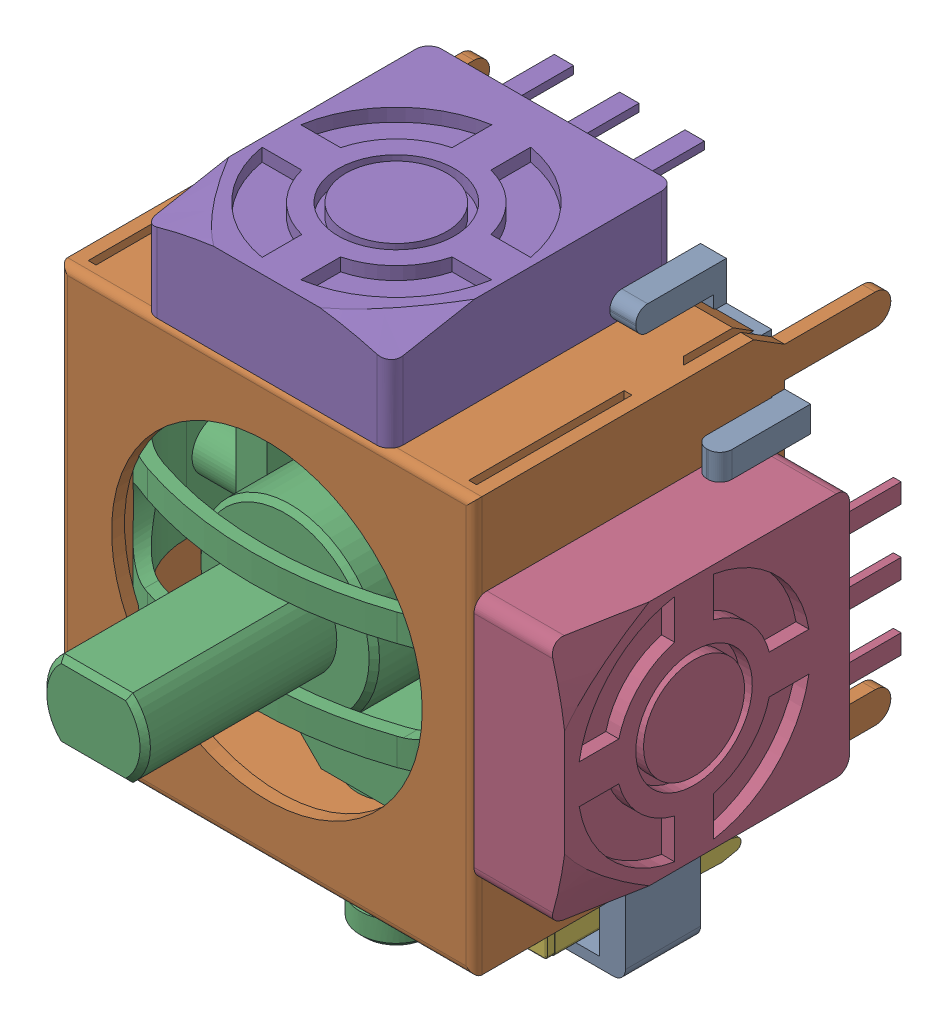
SolidWorks assembly 3D-Analog-Thumb-Joystick, configuration Default. Lengths in mm.
Overall size (20.5 25.8 22.8).
6 component instances, 6 part files, 0 mates.
Components (placement in the parent):
- Baseplate-1: Baseplate [Default] at (0 0 -7) size (18 23.3 3.5)
- Case-1: Case [Default] at origin size (16 16 16.1)
- Rotator-Unit-1: Rotator-Unit [Default] at origin size (16.2 21.5 16.2)
- Potentiometer_01-1: Potentiometer_01 [Default] at (8 0 -6) x (0 1 0) z (0 0 1) size (9.5 3.5 14)
- Potentiometer_02-1: Potentiometer_02 [Default] at (0 8 -6) x (-1 0 0) z (0 0 1) size (9.5 3.5 14)
- Tactile-Switch-1: Tactile-Switch [Default] at (0 -10.8 -6.5) x (1 0 0) z (0 -1 0) size (6.89 8.33 6.01)
